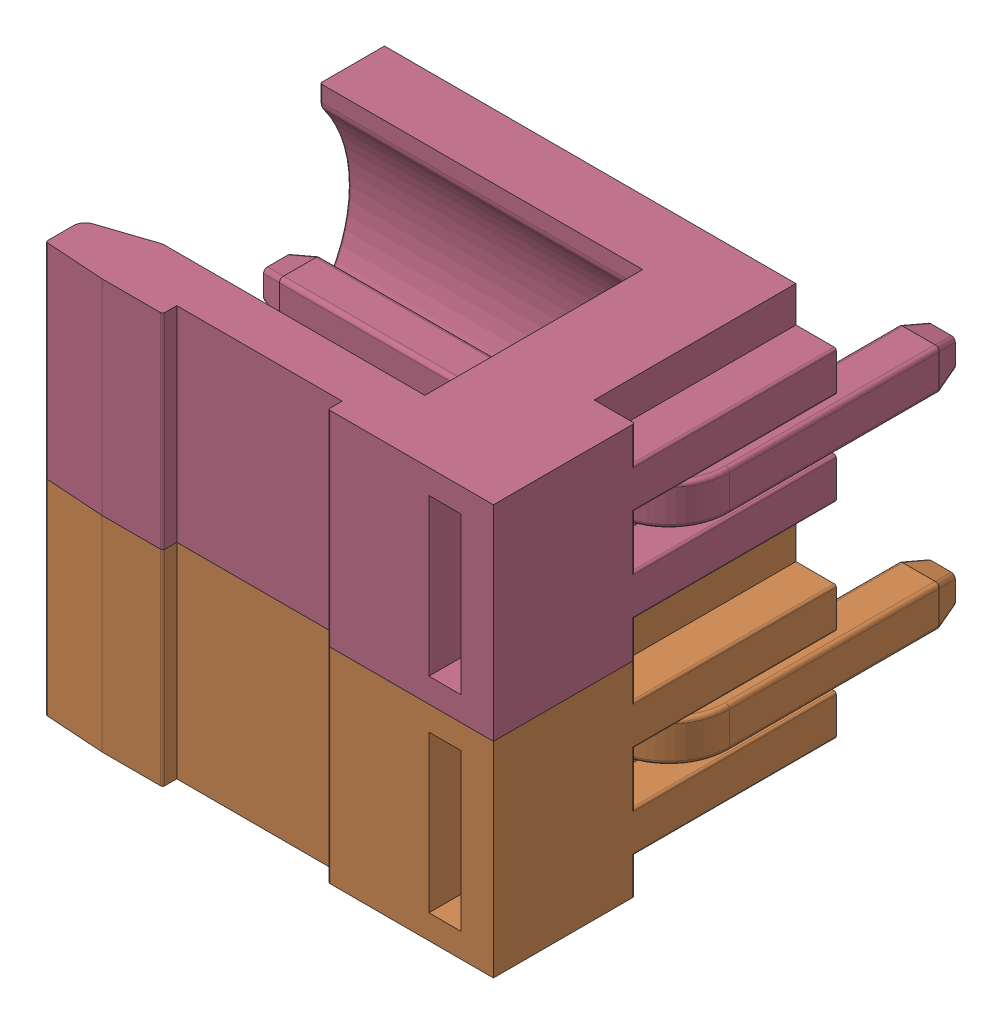
SolidWorks assembly P1, configuration 默认. Lengths in mm.
Overall size (11.3 10.16 11.5).
6 component instances, 2 part files, 0 mates.
Components (placement in the parent):
- KF2EDGK-1P_H-1: KF2EDGK-1P_H [默认] at (46.228 51.308 0) x (0 -1 0) z (0 0 1) size (5.08 11.3 11.5)
  - LOGO横_-_0.5MM-1: LOGO横_-_0.5MM [默认] at (0.513 -1.4708 0) x (-1 0 0) z (0 0 -1) size (1.35 0.5 0.02)
  - KF2EDGK-1P_H-1: KF2EDGK-1P_H [默认] at origin size (5.08 11.3 11.5)
- KF2EDGK-1P_H-2: KF2EDGK-1P_H [默认] at (46.2279 56.3881 0) x (0 -1 0) z (0 0 1) size (5.08 11.3 11.5)
  - LOGO横_-_0.5MM-1: LOGO横_-_0.5MM [默认] at (0.513 -1.4708 0) x (-1 0 0) z (0 0 -1) size (1.35 0.5 0.02)
  - KF2EDGK-1P_H-1: KF2EDGK-1P_H [默认] at origin size (5.08 11.3 11.5)
